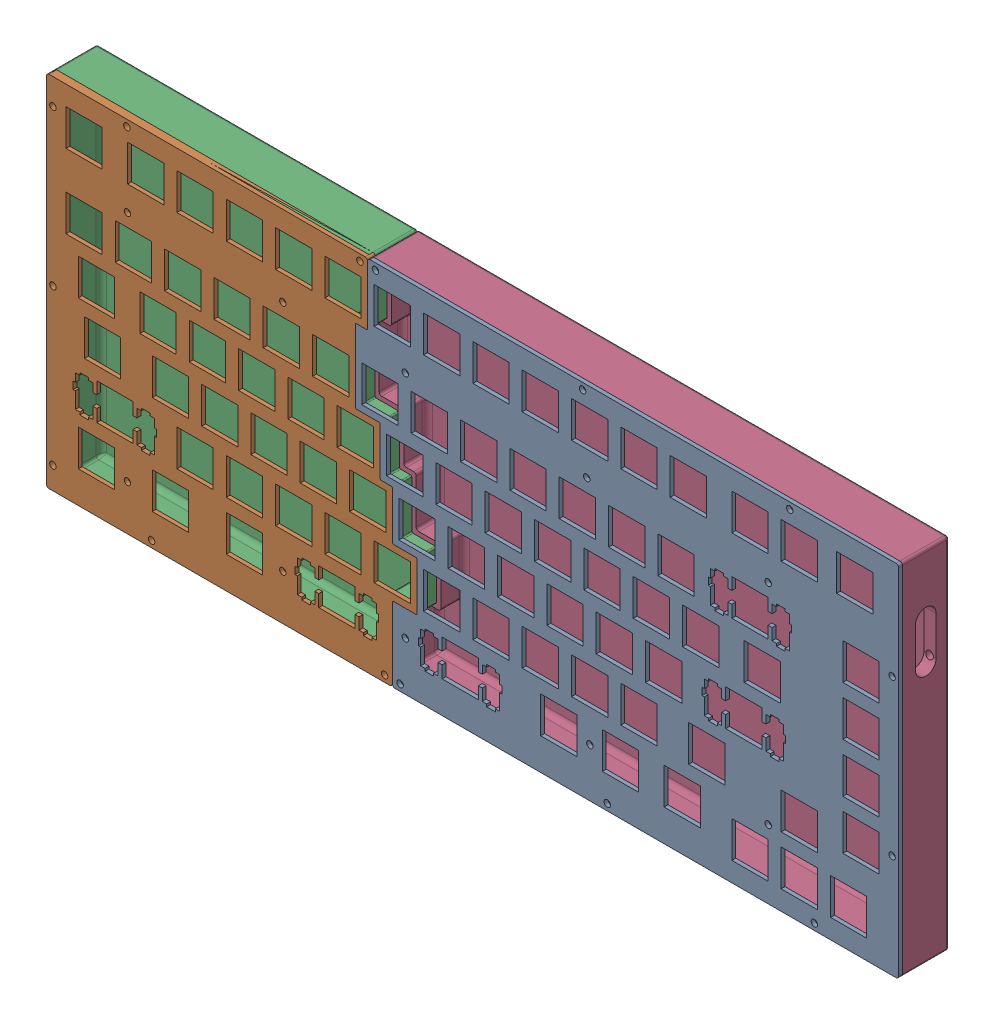
SolidWorks assembly 装配体1, configuration 默认. Lengths in mm.
Overall size (329.09 138.59 19.5).
4 component instances, 4 part files, 9 mates.
Components (placement in the parent):
- 定位板Right-1: 定位板Right [默认] at (-97.4922 -44.4979 0) size (209.79 138.59 1.5)
- 定位板Left-1: 定位板Left [默认] at (-211.7933 -39.5599 0) size (143.11 138.59 3)
- 外壳left-1: 外壳left [默认] at (-211.7933 -39.5599 -3) size (143.11 138.59 18)
- 外壳Right-1: 外壳Right [默认] at (-97.4922 -44.4979 -3) size (209.79 138.59 18)
Mates (geometry in assembly coordinates):
- 重合1: coincident anti-aligned: plane of 定位板Right-1 through (-83.1103 -1.2069 1.5) normal (0 -1 0); plane of 定位板Left-1 through (-83.1103 -1.2069 1.5) normal (0 1 0)
- 同心1: concentric anti-aligned: cylinder of 定位板Left-1 through (-214.1982 79.5231 -1.5) axis (0 0 1) radius 1.25; cylinder of 外壳left-1 through (-214.1982 79.5231 -18) axis (0 0 -1) radius 1.45
- 同心2: concentric anti-aligned: cylinder of 定位板Left-1 through (-185.6353 87.0231 -1.5) axis (0 0 1) radius 1.25; cylinder of 外壳left-1 through (-185.6353 87.0231 -18) axis (0 0 -1) radius 1.45
- 重合4: coincident anti-aligned: plane of 定位板Left-1 through (-211.7933 -39.5599 0) normal (0 0 -1); plane of 外壳left-1 through (-211.7933 -39.5599 0) normal (0 0 1)
- 同心3: concentric anti-aligned: cylinder of 定位板Right-1 through (-80.1103 -46.5638 -1.5) axis (0 0 1) radius 1.25; cylinder of 外壳Right-1 through (-80.1103 -46.5638 -18) axis (0 0 -1) radius 1.45
- 同心5: concentric anti-aligned: cylinder of 定位板Right-1 through (70.3647 87.0231 -1.5) axis (0 0 1) radius 1.25; cylinder of 外壳Right-1 through (70.3647 87.0231 -18) axis (0 0 -1) radius 1.45
- 重合5: coincident anti-aligned: plane of 定位板Right-1 through (-97.4922 -44.4979 0) normal (0 0 -1); plane of 外壳Right-1 through (-97.4922 -44.4979 0) normal (0 0 1)
- 重合6: coincident aligned: plane of 外壳left-1 through (-211.7933 -39.5599 -18) normal (0 0 -1); plane of 外壳Right-1 through (-97.4922 -44.4979 -18) normal (0 0 -1)
- LimitDistance1: limit distance = 0 mm anti-aligned: plane of 外壳Right-1 through (-73.5853 -1.2069 0) normal (-1 0 0); plane of 外壳left-1 through (-73.5853 -1.2069 0) normal (1 0 0)
